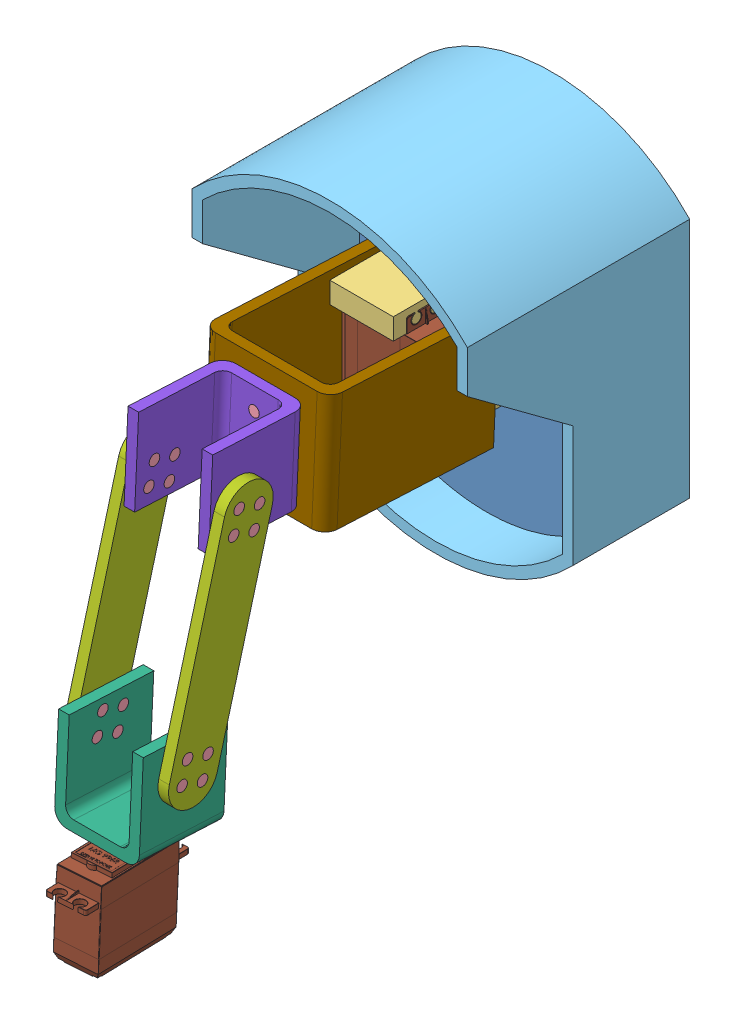
SolidWorks assembly Head_assembly, configuration Valor predeterminado. Lengths in mm.
Overall size (130 251.89 237.83).
54 component instances, 19 part files, 17 mates.
Components (placement in the parent):
- Face_mount-1: Face_mount [Valor predeterminado] at (-60 48.875 -8) size (120 159.58 85)
  - Back_face-1: Back_face [Valor predeterminado] at origin size (120 159.58 8)
  - Frontal_face-1: Frontal_face [Valor predeterminado] at (0 0 -18) size (120 158.33 21)
  - Servo_support-1: Servo_support [Valor predeterminado] at (60 -48.875 8) size (30 62 59)
  - Neck_pin-1: Neck_pin [Valor predeterminado] at (60 -36.875 3) size (5 5 10)
  - Neck_pin-2: Neck_pin [Valor predeterminado] at (60 -60.875 3) size (5 5 10)
- Head_cover-1: Head_cover [Valor predeterminado] at (-60 48.875 -26) size (130 169.58 105)
- Neck_mount-1: Neck_mount [Valor predeterminado] at (3.25 -125.4784 167.3389) x (-1 0 0) z (0 -0.047076 -0.998891) size (60 168.24 156.2)
  - U_fix1-2: U_fix1 [Valor predeterminado] at origin size (40 45.01 40)
  - Neck_support-2: Neck_support [Valor predeterminado] at (-20 -0.5489 -27.4769) x (1 0 0) z (0 -0.214896 0.976637) size (5 123.43 23.43)
  - U_fix2-2: U_fix2 [Valor predeterminado] at (-20 111.368 52.7005) x (1 0 0) z (0 1 0) size (40 45 40)
  - Neck_support-3: Neck_support [Valor predeterminado] at (25 -0.5489 -27.4769) x (1 0 0) z (0 -0.214896 0.976637) size (5 123.43 23.43)
  - Neck_pin-1: Neck_pin [Valor predeterminado] at (15 118.7108 14.1235) x (0 -0.001296 -0.999999) z (1 0 0) size (5 5 10)
  - Neck_pin-4: Neck_pin [Valor predeterminado] at (-25 128.4772 16.2725) x (0 -0.628436 -0.777861) z (1 0 0) size (5 5 10)
  - Neck_pin-5: Neck_pin [Valor predeterminado] at (15 126.3282 26.0388) x (0 -0.628436 -0.777861) z (1 0 0) size (5 5 10)
  - Neck_pin-6: Neck_pin [Valor predeterminado] at (15 116.5619 23.8899) x (0 -0.628436 -0.777861) z (1 0 0) size (5 5 10)
  - Neck_pin-8: Neck_pin [Valor predeterminado] at (-25 35.0805 5.961) x (0 -0.628436 -0.777861) z (1 0 0) size (5 5 10)
  - Neck_pin-9: Neck_pin [Valor predeterminado] at (-25 25.3142 3.812) x (0 -0.628436 -0.777861) z (1 0 0) size (5 5 10)
  - Neck_pin-10: Neck_pin [Valor predeterminado] at (-25 27.4631 -5.9544) x (0 -0.628436 -0.777861) z (1 0 0) size (5 5 10)
  - Neck_pin-11: Neck_pin [Valor predeterminado] at (-25 118.7108 14.1235) x (0 -0.628436 -0.777861) z (1 0 0) size (5 5 10)
  - Neck_pin-12: Neck_pin [Valor predeterminado] at (-25 116.5619 23.8899) x (0 -0.628436 -0.777861) z (1 0 0) size (5 5 10)
  - Neck_pin-13: Neck_pin [Valor predeterminado] at (-25 126.3282 26.0388) x (0 -0.628436 -0.777861) z (1 0 0) size (5 5 10)
  - Neck_pin-14: Neck_pin [Valor predeterminado] at (15 35.0805 5.961) x (0 -0.628436 -0.777861) z (1 0 0) size (5 5 10)
  - Neck_pin-15: Neck_pin [Valor predeterminado] at (15 25.3142 3.812) x (0 -0.628436 -0.777861) z (1 0 0) size (5 5 10)
  - Neck_pin-16: Neck_pin [Valor predeterminado] at (-25 37.2295 -3.8054) x (0 -0.628436 -0.777861) z (1 0 0) size (5 5 10)
  - Neck_pin-17: Neck_pin [Valor predeterminado] at (15 27.4631 -5.9544) x (0 -0.628436 -0.777861) z (1 0 0) size (5 5 10)
  - Neck_pin-18: Neck_pin [Valor predeterminado] at (15 37.2295 -3.8054) x (0 -0.628436 -0.777861) z (1 0 0) size (5 5 10)
  - Neck_pin-19: Neck_pin [Valor predeterminado] at (15 128.4772 16.2725) x (0 -0.628436 -0.777861) z (1 0 0) size (5 5 10)
  - U_fix3-1: U_fix3 [Valor predeterminado] at (-30 158.868 52.7005) x (1 0 0) z (0 -1 0) size (60 80 55)
  - Neck_pin-20: Neck_pin [Valor predeterminado] at (0 121.368 57.7005) x (-0.732963 -0.680269 0) z (0 0 -1) size (5 5 10)
  - Neck_pin-21: Neck_pin [Valor predeterminado] at (0 141.368 57.7005) x (-0.50166 -0.865065 0) z (0 0 -1) size (5 5 10)
  - Servo_star-1: Servo_star [Default] at (-27.5 142.1168 117.2128) x (0 0.500081 -0.865979) z (1 0 0) size (26.52 30 6.7)
  - Servo_star-2: Servo_star [Default] at (0.0006 0 0.001) x (0.500081 0 0.865979) z (0 -1 0) size (26.52 30 6.7)
- main_assembly-2: main_assembly [Default] at (-45.9545 -33.4366 58.6646) x (0 0 -1) z (1 0 0) size (20 53 44.5)
  - main_body-1: main_body [Default] at (15.1003 34.2066 38.7045) size (20 53 41.5)
  - gear-1: gear [Default] at (15.0988 44.3995 70.2045) x (0.991102 -0.133104 0) z (0 0 1) size (5.74 5.74 4.11)
- main_assembly-3: main_assembly [Default] at (-8.6079 -199.9619 216.2713) x (0.997396 -0.003395 -0.072043) z (0 0.998891 -0.047076) size (20 53 44.5)
  - main_body-1: main_body [Default] at (15.1003 34.2066 38.7045) size (20 53 41.5)
  - gear-1: gear [Default] at (15.0988 44.3995 70.2045) x (0.991102 -0.133104 0) z (0 0 1) size (5.74 5.74 4.11)
- RasPi_Camera-1: RasPi_Camera [FOV] at (0 50.74 -24.5517) x (-1 0 0) z (0 -1 0) size (25 8.25 24)
  - RasPi_Camera_Board-1: RasPi_Camera_Board [Standard] at (0 -0.5517 0) x (-1 0 0) z (0 0 -1) size (25 3.5 24)
  - OVA5647-2: OVA5647 [FOV] at (0.0315 -0.3517 0.0586) size (8 5.3 16.75)
    - OVA5647-1: OVA5647 [Standard] at (0.32 0 -0.175) size (8 0.68 8)
    - OVA5647_Housing-1: OVA5647_Housing [Standard] at origin size (8 3.95 8)
    - OVA5647_IR-Glas-1: OVA5647_IR-Glas [Standard] at (0 0.95 0) x (-1 0 0) z (0 0 1) size (6.3 0.35 6.3)
    - OVA5647_Lens-1: OVA5647_Lens [FOV] at (0 3.95 0) size (6 3.35 6)
    - OVA5647_Pigtail-1: OVA5647_Pigtail [Standard] at origin size (8 1.3 16.75)
- LEDs_face_mount-1: LEDs_face_mount [Valor predeterminado] at (0 -5.5 -20.25) x (1 0 0) z (0 1 0) size (96 9.3 64)
  - LED_Matrix-1: LED_Matrix [Valor predeterminado] at (0 -1.5 -16) size (32 9.3 32)
  - LED_Matrix-2: LED_Matrix [Valor predeterminado] at (32 -1.5 -16) size (32 9.3 32)
  - LED_Matrix-3: LED_Matrix [Valor predeterminado] at (-32 -1.5 -16) size (32 9.3 32)
  - LED_Matrix-4: LED_Matrix [Valor predeterminado] at (-32 -1.5 16) size (32 9.3 32)
  - LED_Matrix-5: LED_Matrix [Valor predeterminado] at (32 -1.5 16) size (32 9.3 32)
  - LED_Matrix-6: LED_Matrix [Valor predeterminado] at (0 -1.5 16) size (32 9.3 32)
Mates (geometry in assembly coordinates):
- Coincidente2: coordinate: point of assembly; point of Face_mount-1/Servo_support-1; point of assembly
- Coincidente14: coincident: plane of ? through (0 -11.333 -26) normal (0 0 -1); plane of ? through (0 -11.333 -26) normal (0 0 1)
- Coincidente15: coincident: plane of ? through (-60 48.875 -18) normal (-1 0 0); plane of ? through (-60 48.875 74) normal (1 0 0)
- Concêntrico1: concentric: cylinder of ? through (0 -11.333 -18) axis (0 0 -1) radius 85; cylinder of ? through (0 -11.333 74) axis (0 0 -1) radius 85
- Concêntrico2: concentric: cylinder of assembly; cylinder of assembly; cylinder of Face_mount-1/Servo_support-1 through (15 25.0102 39.0643) axis (-1 0 0) radius 2.25; cylinder of main_assembly-2/main_body-1 through (-16.25 25.0102 39.0643) axis (1 0 0) radius 2.5
- Concêntrico3: concentric: cylinder of assembly; cylinder of assembly; cylinder of Face_mount-1/Servo_support-1 through (15 -23.4702 48.0643) axis (-1 0 0) radius 2.25; cylinder of main_assembly-2/main_body-1 through (-16.25 -23.4702 48.0643) axis (1 0 0) radius 2.5
- Distância2: distance = 0.2 mm: line of assembly; line of assembly; line of main_assembly-2/main_body-1 through (15 -19.1907 34.6643) axis (0 -1 0); line of Face_mount-1/Servo_support-1 through (15 -21 34.4643) axis (0 -1 0)
- Paralelo4: parallel: plane of assembly; plane of assembly; plane of Neck_mount-1/U_fix1-2 through (-16.75 -128.9171 147.4788) normal (0 -0.998891 0.047076); plane of main_assembly-3/main_body-1 through (3.986 -131.7424 177.8106) normal (0 0.998891 -0.047076)
- Coincidente24: coincident: plane of assembly; plane of assembly; plane of Neck_mount-1/Servo_star-2 through (7.4999 -127.6292 174.8077) normal (0 -0.998891 0.047076); plane of main_assembly-3/gear-1 through (3.2494 -127.9757 167.4555) normal (0 0.998891 -0.047076)
- Coincidente25: coincident: circle of assembly; circle of assembly; circle of Neck_mount-1/Servo_star-2; circle of main_assembly-3/gear-1
- Coincidente27: coincident: plane of assembly; plane of assembly; plane of Neck_mount-1/Servo_star-1 through (28.25 6.3708 36.4136) normal (-1 0 0); plane of main_assembly-2/gear-1 through (28.25 10.9629 43.5658) normal (1 0 0)
- Concêntrico4: concentric: circle of assembly; circle of assembly; circle of Neck_mount-1/Servo_star-1; circle of main_assembly-2/main_body-1
- Coincidente34: coincident: plane of ? through (-60 48.875 -24) normal (0 0 1); plane of RasPi_Camera-1/RasPi_Camera_Board-1 through (0 50.74 -24) normal (0 0 -1)
- Concêntrico11: concentric: cylinder of ? through (10.5 50.74 -26) axis (0 0 1) radius 1.4; cylinder of RasPi_Camera-1/RasPi_Camera_Board-1 through (10.5 50.74 -23.1) axis (0 0 -1) radius 1.05
- Concêntrico12: concentric: cylinder of ? through (-10.5 38.24 -26) axis (0 0 1) radius 1.4; cylinder of RasPi_Camera-1/RasPi_Camera_Board-1 through (-10.5 38.24 -23.1) axis (0 0 -1) radius 1.05
- Coincidente35: coincident: line of ? through (-48 -37.5 -26) axis (1 0 0); line of LEDs_face_mount-1/LED_Matrix-1 through (16 -37.5 -26) axis (-1 0 0)
- Coincidente36: coincident: line of ? through (48 -37.5 -26) axis (0 1 0); line of LEDs_face_mount-1/LED_Matrix-2 through (48 -5.5 -26) axis (0 -1 0)
